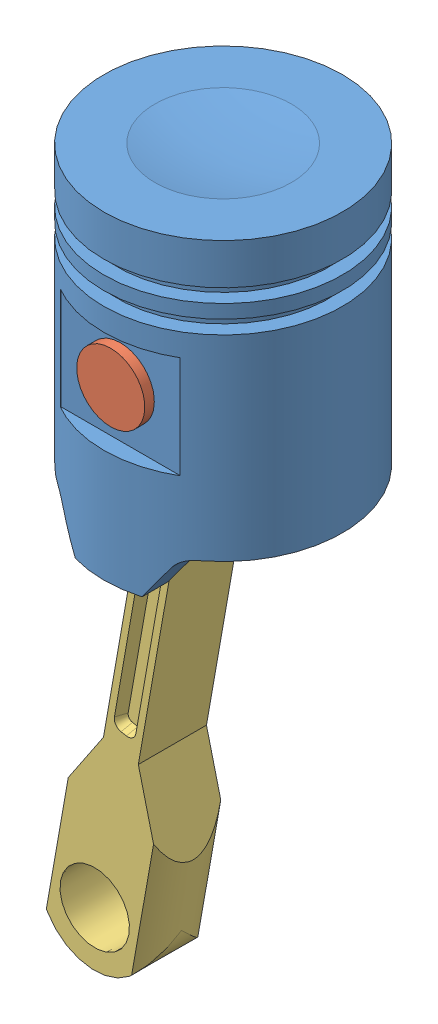
SolidWorks assembly Assem3, configuration Default. Lengths in mm.
Overall size (51.58 140.79 44.45).
3 component instances, 3 part files, 5 mates.
Components (placement in the parent):
- V6_Piston-1: V6_Piston [Default] at (7.9864 12.0599 45.8043) size (44.45 59.44 44.45)
- V6_pin-1: V6_pin [Default] at (7.9864 42.5399 24.8493) x (0.957589 0.288138 0) z (0 0 1) size (12.7 12.7 41.91)
- V6_Connecting_Rod-1: V6_Connecting_Rod [Default] at (-9.6041 -57.5258 52.1543) x (0.984898 -0.173136 0) z (0 0 1) size (20.32 121.92 12.7)
Mates (geometry in assembly coordinates):
- Concentric1: concentric anti-aligned: cylinder of V6_Piston-1 through (7.9864 42.5399 23.5793) axis (0 0 1) radius 6.35; cylinder of V6_pin-1 through (7.9864 42.5399 66.7593) axis (0 0 -1) radius 6.35
- Concentric4: concentric anti-aligned: cylinder of V6_Piston-1 through (7.9864 42.5399 23.5793) axis (0 0 1) radius 6.35; cylinder of V6_pin-1 through (7.9864 42.5399 66.7593) axis (0 0 -1) radius 6.35
- Width2: width aligned: plane of V6_pin-1 through (7.9864 42.5399 66.7593) normal (0 0 1); plane of V6_pin-1 through (7.9864 42.5399 24.8493) normal (0 0 -1); plane of V6_Piston-1 through (7.9864 12.0599 64.9813) normal (0 0 1); plane of V6_Piston-1 through (7.9864 12.0599 26.6273) normal (0 0 -1)
- Concentric6: concentric anti-aligned: cylinder of V6_pin-1 through (7.9864 42.5399 66.7593) axis (0 0 -1) radius 6.35; cylinder of V6_Connecting_Rod-1 through (7.9864 42.5399 39.4543) axis (0 0 1) radius 6.477
- Width3: width aligned: plane of V6_pin-1 through (7.9864 42.5399 24.8493) normal (0 0 -1); plane of V6_pin-1 through (7.9864 42.5399 66.7593) normal (0 0 1); plane of V6_Connecting_Rod-1 through (-9.6041 -57.5258 39.4543) normal (0 0 -1); plane of V6_Connecting_Rod-1 through (-9.6041 -57.5258 52.1543) normal (0 0 1)
